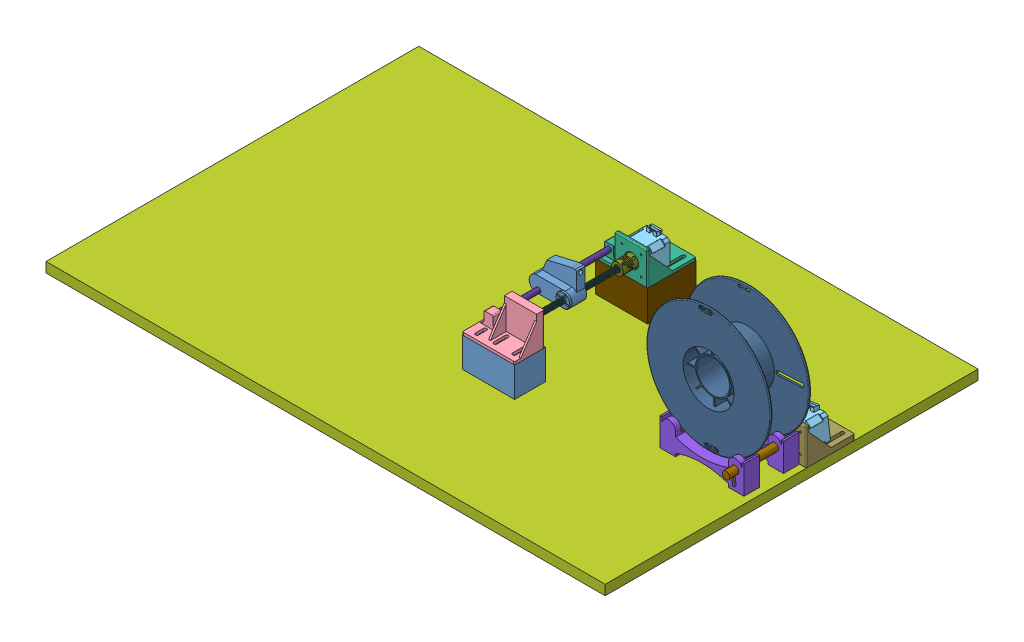
SolidWorks assembly Spooling assembly, configuration Default. Lengths in mm.
Overall size (926.02 244.81 600).
87 component instances, 37 part files, 29 mates.
Components (placement in the parent):
- Filament Adjuster-1: Filament Adjuster [Default] at (79.9822 23.1667 -31.1249) x (0 0 -1) z (1 0 0) size (25 51.72 67.71)
- Ball Bearing 8 x 22 x 7mm-1: Ball Bearing 8 x 22 x 7mm [Default] at (103.7322 37.3167 44.9222) x (0 0 1) z (-0.919598 -0.39286 0) size (7 22 22)
  - 608-2RS Skate Board Ball Bearing.step-1: 608-2RS Skate Board Ball Bearing.step [Default] at origin size (7 22 22)
    - Ball 001.step-1: Ball 001.step [Default] at (0 0 7.5) size (4 4 4)
    - Ball 002.step-1: Ball 002.step [Default] at (0 5.8637 4.6762) x (1 0 0) z (0 0.781831 0.62349) size (4 4 4)
    - Ball 003.step-1: Ball 003.step [Default] at (0 7.312 -1.6689) x (1 0 0) z (0 0.974928 -0.222521) size (4 4 4)
    - Ball 004.step-1: Ball 004.step [Default] at (0 3.2541 -6.7573) x (1 0 0) z (0 0.433884 -0.900969) size (4 4 4)
    - Ball 005.step-1: Ball 005.step [Default] at (0 -3.2541 -6.7573) x (1 0 0) z (0 -0.433884 -0.900969) size (4 4 4)
    - Ball 006.step-1: Ball 006.step [Default] at (0 -7.312 -1.6689) x (1 0 0) z (0 -0.974928 -0.222521) size (4 4 4)
    - Ball 007.step-1: Ball 007.step [Default] at (0 -5.8637 4.6762) x (1 0 0) z (0 -0.781831 0.62349) size (4 4 4)
    - Outer Ring001.step-1: Outer Ring001.step [Default] at origin size (7 22 22)
    - Inner Ring001.step-1: Inner Ring001.step [Default] at origin size (7 12 12)
    - Seal 001.step-1: Seal 001.step [Default] at origin size (0.6 19 19)
    - Seal 002.step-1: Seal 002.step [Default] x (-1 0 0) z (0 0 -1) size (0.6 19 19)
    - Cage 001.step-1: Cage 001.step [Default] at origin size (2.31 17.85 17.41)
    - Cage clone 002.step-1: Cage clone 002.step [Default] x (-1 0 0) z (0 0 1) size (2.31 17.85 17.41)
    - Rivet 002.step-1: Rivet 002.step [Default] at (0 3.2541 6.7573) x (1 0 0) z (0 0.433884 0.900969) size (0.8 0.8 0.8)
    - Rivet 001.step-1: Rivet 001.step [Default] at (0 -3.2541 6.7573) x (1 0 0) z (0 -0.433884 0.900969) size (0.8 0.8 0.8)
    - Rivet 007.step-1: Rivet 007.step [Default] at (0 5.8637 -4.6762) x (1 0 0) z (0 0.781831 -0.62349) size (0.8 0.8 0.8)
    - Rivet 006.step-1: Rivet 006.step [Default] at (0 7.312 1.6689) x (1 0 0) z (0 0.974928 0.222521) size (0.8 0.8 0.8)
    - Rivet 005.step-1: Rivet 005.step [Default] at (0 -7.312 1.6689) x (1 0 0) z (0 -0.974928 0.222521) size (0.8 0.8 0.8)
    - Rivet 004.step-1: Rivet 004.step [Default] at (0 -5.8637 -4.6762) x (1 0 0) z (0 -0.781831 -0.62349) size (0.8 0.8 0.8)
    - Rivet 003.step-1: Rivet 003.step [Default] at (0 0 -7.5) x (1 0 0) z (0 0 -1) size (0.8 0.8 0.8)
- Support for bearing and aluminium shaft-1: Support for bearing and aluminium shaft [Default] at (87.7322 11.6667 64.4222) x (0 0 1) z (-1 0 0) size (48 53 84)
- nema 17 model v2-1: nema 17 model v2 [Default] at (103.9822 37.3167 -166.7778) size (41.5 47.8 59.9)
- Motor holder for threaded rod and straight rod-1: Motor holder for threaded rod and straight rod [Default] at (87.7322 11.6667 -149.5778) x (-1 0 0) z (0 0 -1) size (84 53 78)
- Wood chassis-1: Wood chassis [Default] at (8.2548 -54.3333 -28.8819) size (900 16 600)
- Spooling sub-assembly-1: Spooling sub-assembly [Default] at (308.2261 -34.2774 -8.375) size (210.04 228.81 182.5)
  - Spool Holder-1: Spool Holder [Default] at (114.0287 -4.056 45.1541) size (135 46 25)
  - Spool Holder-2: Spool Holder [Default] at (114.0287 -4.056 -18.4114) size (135 46 25)
  - Shaft for motor-1: Shaft for motor [Default] at (125.0426 25.8335 -39.746) x (0.992208 0.124596 0) z (0.124596 -0.992208 0) size (11.75 100 11.75)
  - Ball Bearing 8 x 22 x 7mm-1: Ball Bearing 8 x 22 x 7mm [Default] at (18.0287 25.944 33.2041) x (0 0 1) z (-0.076409 0.997077 0) size (7 22 22)
    - 608-2RS Skate Board Ball Bearing.step-1: 608-2RS Skate Board Ball Bearing.step [Default] at origin size (7 22 22)
      - Ball 001.step-1: Ball 001.step [Default] at (0 0 7.5) size (4 4 4)
      - Ball 002.step-1: Ball 002.step [Default] at (0 5.8637 4.6762) x (1 0 0) z (0 0.781831 0.62349) size (4 4 4)
      - Ball 003.step-1: Ball 003.step [Default] at (0 7.312 -1.6689) x (1 0 0) z (0 0.974928 -0.222521) size (4 4 4)
      - Ball 004.step-1: Ball 004.step [Default] at (0 3.2541 -6.7573) x (1 0 0) z (0 0.433884 -0.900969) size (4 4 4)
      - Ball 005.step-1: Ball 005.step [Default] at (0 -3.2541 -6.7573) x (1 0 0) z (0 -0.433884 -0.900969) size (4 4 4)
      - Ball 006.step-1: Ball 006.step [Default] at (0 -7.312 -1.6689) x (1 0 0) z (0 -0.974928 -0.222521) size (4 4 4)
      - Ball 007.step-1: Ball 007.step [Default] at (0 -5.8637 4.6762) x (1 0 0) z (0 -0.781831 0.62349) size (4 4 4)
      - Outer Ring001.step-1: Outer Ring001.step [Default] at origin size (7 22 22)
      - Inner Ring001.step-1: Inner Ring001.step [Default] at origin size (7 12 12)
      - Seal 001.step-1: Seal 001.step [Default] at origin size (0.6 19 19)
      - Seal 002.step-1: Seal 002.step [Default] x (-1 0 0) z (0 0 -1) size (0.6 19 19)
      - Cage 001.step-1: Cage 001.step [Default] at origin size (2.31 17.85 17.41)
      - Cage clone 002.step-1: Cage clone 002.step [Default] x (-1 0 0) z (0 0 1) size (2.31 17.85 17.41)
      - Rivet 002.step-1: Rivet 002.step [Default] at (0 3.2541 6.7573) x (1 0 0) z (0 0.433884 0.900969) size (0.8 0.8 0.8)
      - Rivet 001.step-1: Rivet 001.step [Default] at (0 -3.2541 6.7573) x (1 0 0) z (0 -0.433884 0.900969) size (0.8 0.8 0.8)
      - Rivet 007.step-1: Rivet 007.step [Default] at (0 5.8637 -4.6762) x (1 0 0) z (0 0.781831 -0.62349) size (0.8 0.8 0.8)
      - Rivet 006.step-1: Rivet 006.step [Default] at (0 7.312 1.6689) x (1 0 0) z (0 0.974928 0.222521) size (0.8 0.8 0.8)
      - Rivet 005.step-1: Rivet 005.step [Default] at (0 -7.312 1.6689) x (1 0 0) z (0 -0.974928 0.222521) size (0.8 0.8 0.8)
      - Rivet 004.step-1: Rivet 004.step [Default] at (0 -5.8637 -4.6762) x (1 0 0) z (0 -0.781831 -0.62349) size (0.8 0.8 0.8)
      - Rivet 003.step-1: Rivet 003.step [Default] at (0 0 -7.5) x (1 0 0) z (0 0 -1) size (0.8 0.8 0.8)
  - Ball Bearing 8 x 22 x 7mm-2: Ball Bearing 8 x 22 x 7mm [Default] at (18.0287 25.944 -30.3614) x (0 0 1) z (-1 0 0) size (7 22 22)
    - 608-2RS Skate Board Ball Bearing.step-1: 608-2RS Skate Board Ball Bearing.step [Default] at origin size (7 22 22)
      - Ball 001.step-1: Ball 001.step [Default] at (0 0 7.5) size (4 4 4)
      - Ball 002.step-1: Ball 002.step [Default] at (0 5.8637 4.6762) x (1 0 0) z (0 0.781831 0.62349) size (4 4 4)
      - Ball 003.step-1: Ball 003.step [Default] at (0 7.312 -1.6689) x (1 0 0) z (0 0.974928 -0.222521) size (4 4 4)
      - Ball 004.step-1: Ball 004.step [Default] at (0 3.2541 -6.7573) x (1 0 0) z (0 0.433884 -0.900969) size (4 4 4)
      - Ball 005.step-1: Ball 005.step [Default] at (0 -3.2541 -6.7573) x (1 0 0) z (0 -0.433884 -0.900969) size (4 4 4)
      - Ball 006.step-1: Ball 006.step [Default] at (0 -7.312 -1.6689) x (1 0 0) z (0 -0.974928 -0.222521) size (4 4 4)
      - Ball 007.step-1: Ball 007.step [Default] at (0 -5.8637 4.6762) x (1 0 0) z (0 -0.781831 0.62349) size (4 4 4)
      - Outer Ring001.step-1: Outer Ring001.step [Default] at origin size (7 22 22)
      - Inner Ring001.step-1: Inner Ring001.step [Default] at origin size (7 12 12)
      - Seal 001.step-1: Seal 001.step [Default] at origin size (0.6 19 19)
      - Seal 002.step-1: Seal 002.step [Default] x (-1 0 0) z (0 0 -1) size (0.6 19 19)
      - Cage 001.step-1: Cage 001.step [Default] at origin size (2.31 17.85 17.41)
      - Cage clone 002.step-1: Cage clone 002.step [Default] x (-1 0 0) z (0 0 1) size (2.31 17.85 17.41)
      - Rivet 002.step-1: Rivet 002.step [Default] at (0 3.2541 6.7573) x (1 0 0) z (0 0.433884 0.900969) size (0.8 0.8 0.8)
      - Rivet 001.step-1: Rivet 001.step [Default] at (0 -3.2541 6.7573) x (1 0 0) z (0 -0.433884 0.900969) size (0.8 0.8 0.8)
      - Rivet 007.step-1: Rivet 007.step [Default] at (0 5.8637 -4.6762) x (1 0 0) z (0 0.781831 -0.62349) size (0.8 0.8 0.8)
      - Rivet 006.step-1: Rivet 006.step [Default] at (0 7.312 1.6689) x (1 0 0) z (0 0.974928 0.222521) size (0.8 0.8 0.8)
      - Rivet 005.step-1: Rivet 005.step [Default] at (0 -7.312 1.6689) x (1 0 0) z (0 -0.974928 0.222521) size (0.8 0.8 0.8)
      - Rivet 004.step-1: Rivet 004.step [Default] at (0 -5.8637 -4.6762) x (1 0 0) z (0 -0.781831 -0.62349) size (0.8 0.8 0.8)
      - Rivet 003.step-1: Rivet 003.step [Default] at (0 0 -7.5) x (1 0 0) z (0 0 -1) size (0.8 0.8 0.8)
  - esun spool-1: esun spool [Default] at (71.028 119.733 1.7195) x (0 0 1) z (-0.998672 -0.051512 0) size (65 200 200)
  - 3D printed bearing ofr spooling system-1: 3D printed bearing ofr spooling system [Default] at (125.0287 25.944 30.4041) x (0 0 1) z (0.789788 -0.61338 0) size (6 22 22)
  - 3D printed bearing ofr spooling system-2: 3D printed bearing ofr spooling system [Default] at (125.0287 25.944 -33.1614) x (0 0 1) z (-0.554271 -0.832336 0) size (6 22 22)
  - nema 17 model v2-1: nema 17 model v2 [Default] at (125.0287 25.944 -85.4479) x (0.992208 0.124596 0) z (0 0 1) size (41.5 47.8 59.9)
  - Motor holder for spool-1: Motor holder for spool [Default] at (108.0287 -4.056 -68.2479) x (-1 0 0) z (0 0 -1) size (53 57.35 78)
  - Spool shaft connector-1: Spool shaft connector [Default] at (126.015 6.0509 50.254) x (0.992208 0.124596 0) z (0 0 1) size (2.75 20 2.75)
- t8 screw nut-1: t8 screw nut [Default] at (103.9822 37.3167 -13.6249) x (0 0 -1) z (0.423018 0.906121 0) size (15.1 22 22)
- T8 200mm rod-1: T8 200mm rod [Default] at (91.9263 28.3917 43.1222) x (0.803729 0.594995 0) z (-0.594995 0.803729 0) size (8.03 150.1 8.02)
- Flexible Coupler Body-1: Flexible Coupler Body [Default] at (103.9822 37.3167 -115.0778) x (0.601281 0.799038 0) z (0.799038 -0.601281 0) size (19.87 25 19.54)
- Aluminium shaft-1: Aluminium shaft [Default] at (60.7322 28.1667 57.4222) x (1 0 0) z (0 1 0) size (8 200 8)
- Base for Motor holder (and rod)-1: Base for Motor holder (and rod) [Default] at (45.7322 -38.3333 -125.5778) size (84 50 78)
- Base for Bearing and rod-2: Base for Bearing and rod [Default] at (45.7322 11.6667 88.4222) x (1 0 0) z (0 1 0) size (84 50 48)
Mates (geometry in assembly coordinates):
- Parallel1: parallel aligned: line of Motor holder for threaded rod and straight rod-1 through (127.7322 16.1667 -203.5778) axis (-1 0 0); line of Wood chassis-1 through (458.2548 -38.3333 -328.8819) axis (-1 0 0)
- Parallel2: parallel aligned: line of nema 17 model v2-1 through (120.068 58.0667 -129.5778) axis (-1 0 0); line of Motor holder for threaded rod and straight rod-1 through (127.7322 64.6667 -129.5778) axis (-1 0 0)
- Concentric2: concentric anti-aligned: circle of nema 17 model v2-1; circle of Motor holder for threaded rod and straight rod-1
- Coincident6: coincident anti-aligned: plane of nema 17 model v2-1 through (103.9822 37.3167 -129.5778) normal (0 0 1); plane of Motor holder for threaded rod and straight rod-1 through (129.7322 64.6667 -129.5778) normal (0 0 -1)
- Concentric3: concentric anti-aligned: circle of Ball Bearing 8 x 22 x 7mm-1/608-2RS Skate Board Ball Bearing.step-1/Outer Ring001.step-1; circle of Support for bearing and aluminium shaft-1
- Coincident7: coincident anti-aligned: plane of Ball Bearing 8 x 22 x 7mm-1/608-2RS Skate Board Ball Bearing.step-1/Seal 001.step-1 through (103.7322 37.3167 48.4222) normal (0 0 1); plane of Support for bearing and aluminium shaft-1 through (103.7322 37.3167 48.4222) normal (0 0 -1)
- Parallel4: parallel anti-aligned: line of Support for bearing and aluminium shaft-1 through (127.7322 11.6667 40.4222) axis (-1 0 0); line of Wood chassis-1 through (-441.7452 -38.3333 271.1181) axis (1 0 0)
- Concentric4: concentric anti-aligned: circle of Support for bearing and aluminium shaft-1; circle of Motor holder for threaded rod and straight rod-1
- Coincident13: coincident anti-aligned: plane of Wood chassis-1 through (8.2548 -38.3333 -28.8819) normal (0 1 0); plane of Spooling sub-assembly-1/Part2-1 through (422.2548 -38.3333 36.779) normal (0 -1 0)
- Coincident14: coincident aligned: line of Wood chassis-1 through (458.2548 -38.3333 271.1181) axis (0 0 -1); line of Spooling sub-assembly-1/Motor holder for spool-1 through (458.2548 -38.3333 -54.623) axis (0 0 -1)
- Concentric6: concentric aligned: circle of Filament Adjuster-1; circle of t8 screw nut-1
- Coincident17: coincident anti-aligned: plane of Filament Adjuster-1 through (55.9822 48.1667 -18.6249) normal (0 0 1); plane of t8 screw nut-1 through (103.9822 37.3167 -18.6249) normal (0 0 -1)
- Concentric7: concentric anti-aligned: cylinder of nema 17 model v2-1 through (103.9822 37.3167 -131.5778) axis (0 0 1) radius 2.5; cylinder of Flexible Coupler Body-1 through (103.9822 37.3167 -102.5778) axis (0 0 -1) radius 9.5
- Concentric8: concentric anti-aligned: circle of Filament Adjuster-1; circle of Motor holder for threaded rod and straight rod-1
- Concentric10: concentric anti-aligned: cylinder of Filament Adjuster-1 through (103.9822 37.3167 -18.6249) axis (0 0 -1) radius 4.5; cylinder of Flexible Coupler Body-1 through (103.9822 37.3167 -120.0778) axis (0 0 1) radius 5
- Coincident20: coincident anti-aligned: plane of nema 17 model v2-1 through (103.9822 37.3167 -127.5778) normal (0 0 1); plane of Flexible Coupler Body-1 through (103.9822 37.3167 -127.5778) normal (0 0 -1)
- Coincident21: coincident anti-aligned: plane of Motor holder for threaded rod and straight rod-1 through (60.7322 28.1667 -142.5778) normal (0 0 1); plane of Aluminium shaft-1 through (60.7322 28.1667 -142.5778) normal (0 0 -1)
- Concentric11: concentric aligned: cylinder of Motor holder for threaded rod and straight rod-1 through (60.7322 28.1667 -142.5778) axis (0 0 1) radius 4; cylinder of Aluminium shaft-1 through (60.7322 28.1667 -142.5778) axis (0 0 1) radius 4
- Coincident22: coincident anti-aligned: plane of Support for bearing and aluminium shaft-1 through (60.7322 28.1667 57.4222) normal (0 0 -1); plane of Aluminium shaft-1 through (60.7322 28.1667 57.4222) normal (0 0 1)
- Coincident23: coincident anti-aligned: plane of nema 17 model v2-1 through (103.9822 37.3167 -106.8778) normal (0 0 1); plane of T8 200mm rod-1 through (103.9822 37.3167 -106.8778) normal (0 0 -1)
- Concentric12: concentric anti-aligned: cylinder of T8 200mm rod-1 through (103.9822 37.3167 43.1222) axis (0 0 -1) radius 3.9625; cylinder of Flexible Coupler Body-1 through (103.9822 37.3167 -120.0778) axis (0 0 1) radius 5
- Coincident24: coincident anti-aligned: plane of Wood chassis-1 through (8.2548 -38.3333 -28.8819) normal (0 1 0); plane of Base for Motor holder (and rod)-1 through (45.7322 -38.3333 -125.5778) normal (0 -1 0)
- Coincident25: coincident anti-aligned: plane of Motor holder for threaded rod and straight rod-1 through (87.7322 11.6667 -149.5778) normal (0 -1 0); plane of Base for Motor holder (and rod)-1 through (45.7322 11.6667 -125.5778) normal (0 1 0)
- Coincident26: coincident aligned: line of Motor holder for threaded rod and straight rod-1 through (127.7322 11.6667 -203.5778) axis (-1 0 0); line of Base for Motor holder (and rod)-1 through (129.7322 11.6667 -203.5778) axis (-1 0 0)
- Coincident27: coincident aligned: line of Motor holder for threaded rod and straight rod-1 through (129.7322 11.6667 -127.5778) axis (0 0 -1); line of Base for Motor holder (and rod)-1 through (129.7322 11.6667 -125.5778) axis (0 0 -1)
- Coincident28: coincident anti-aligned: plane of Support for bearing and aluminium shaft-1 through (87.7322 11.6667 64.4222) normal (0 -1 0); plane of Base for Bearing and rod-2 through (45.7322 11.6667 38.4222) normal (0 1 0)
- Parallel5: parallel anti-aligned: plane of Wood chassis-1 through (8.2548 -38.3333 -28.8819) normal (0 1 0); plane of Base for Bearing and rod-2 through (45.7322 -36.3333 38.4222) normal (0 -1 0)
- Coincident31: coincident aligned: line of Support for bearing and aluminium shaft-1 through (47.7322 11.6667 88.4222) axis (1 0 0); line of Base for Bearing and rod-2 through (45.7322 11.6667 88.4222) axis (1 0 0)
- Coincident32: coincident anti-aligned: line of Support for bearing and aluminium shaft-1 through (129.7322 11.6667 86.4222) axis (0 0 -1); line of Base for Bearing and rod-2 through (129.7322 11.6667 38.4222) axis (0 0 1)
